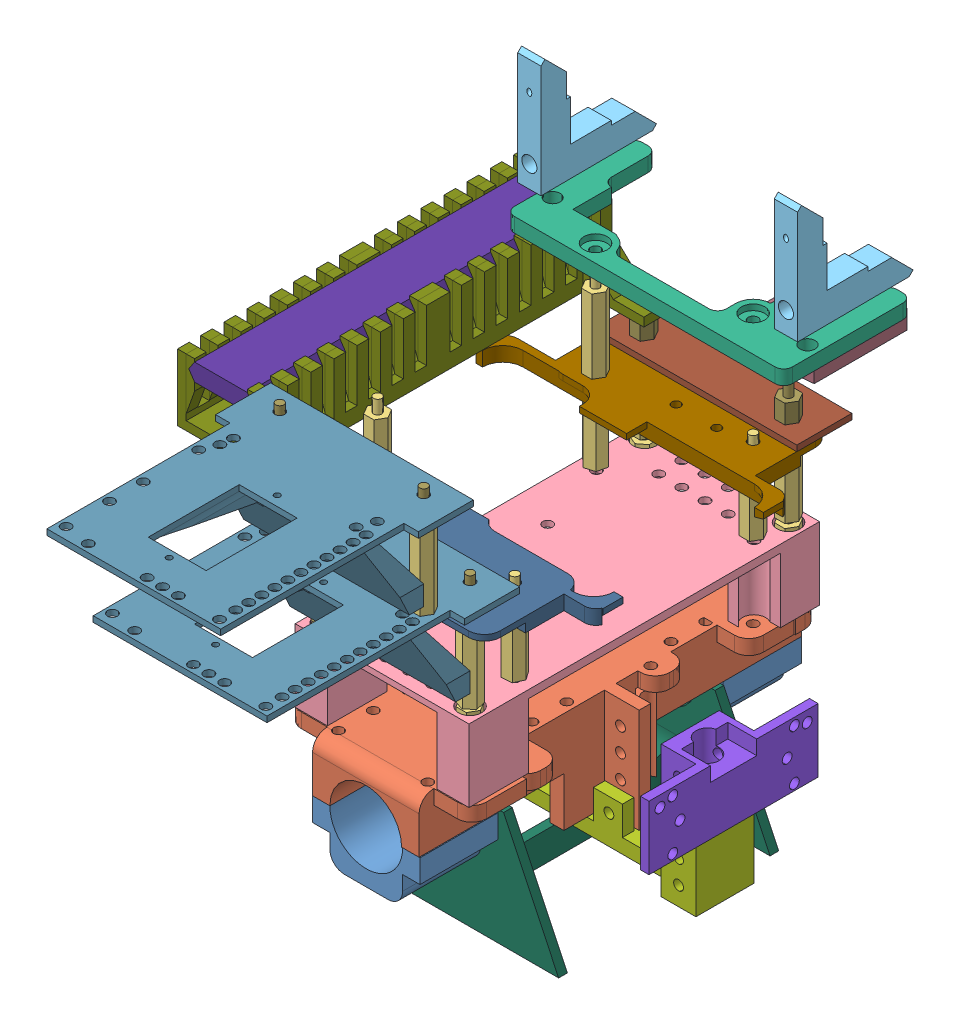
SolidWorks assembly Assemblage5, configuration Défaut. Lengths in mm.
Overall size (134 197.56 254.27).
40 component instances, 17 part files, 85 mates.
Components (placement in the parent):
- Pièce2b-1: Pièce2b [Défaut] at (-3.667 32.9905 263.0949) x (1 0 0) z (0 0 -1) size (37.12 18 27)
- Pièce2b-2: Pièce2b [Défaut] at (-3.9871 32.9905 131.0949) x (-1 0 0) z (0 0 1) size (37.12 18 27)
- Pièce1c-1: Pièce1c [Défaut] at (-3.827 32.9905 131.0949) size (72.97 36 132.85)
- exagone1-6: exagone1 [Défaut] at (-27.807 77.9905 235.0174) x (-0.458196 0 -0.888851) z (0 1 0) size (7.1 6.15 30.2)
- exagone1-7: exagone1 [Défaut] at (-27.807 77.9905 159.7774) x (0.957839 0 -0.287305) z (0 1 0) size (7.1 6.15 30.2)
- exagone1-8: exagone1 [Défaut] at (20.393 77.9905 153.5574) x (1 0 0) z (0 1 0) size (7.1 6.15 30.2)
- exagone1-9: exagone1 [Défaut] at (20.6941 77.236 236.1549) x (-0.419433 0 0.907787) z (0 1 0) size (7.1 6.15 30.2)
- exagone1-10: exagone1 [Défaut] at (-27.807 105.4905 235.0174) x (1 0 0) z (0 1 0) size (7.1 6.15 30.2)
- exagone1-11: exagone1 [Défaut] at (-27.807 105.4905 159.7774) x (1 0 0.000039) z (0 1 0) size (7.1 6.15 30.2)
- support_batterie_portable1-1: support_batterie_portable1 [Défaut] at (10.2075 50.9905 203.6226) x (1 0 0) z (0 1 0) size (60 121.05 25)
- exagone1-12: exagone1 [Défaut] at (21.173 50.9905 142.0949) x (1 0 0) z (0 1 0) size (7.1 6.15 30.2)
- exagone1-13: exagone1 [Défaut] at (-28.827 50.9905 142.0949) x (0.791864 0 -0.610698) z (0 1 0) size (7.1 6.15 30.2)
- exagone1-14: exagone1 [Défaut] at (-28.827 50.9905 252.0949) x (1 0 0) z (0 1 0) size (7.1 6.15 30.2)
- exagone1-15: exagone1 [Défaut] at (21.173 50.9905 252.0949) x (1 0 0) z (0 1 0) size (7.1 6.15 30.2)
- support02-1: support02 [Défaut] at (-44.8171 185.6386 155.3707) x (-0.004818 -0.707107 -0.70709) z (-0.999977 0 0.006814) size (54.89 29.35 8)
- support02-2: support02 [Défaut] at (43.1809 185.6386 154.7711) x (-0.004818 -0.707107 -0.70709) z (-0.999977 0 0.006814) size (54.89 29.35 8)
- ecran supplementaire2-1: ecran supplementaire2 [Défaut] at (39.1725 138.7883 153.5574) x (-1 0 0) z (0 1 0) size (96 44.22 5)
- stabilizer2-1: stabilizer2 [Défaut] at (-4.2222 13.9905 199.0949) x (1 0 0) z (0 -1 0) size (120.8 20 21)
- support_sensor_01-1: support_sensor_01 [Défaut] at (44.1778 32.671 209.0949) x (0 0 -1) z (1 0 0) size (58.42 22 15)
- support_raspberry_gouche_01-1: support_raspberry_gouche_01 [Défaut] at (79.6593 103.4905 220.4967) x (1 0 0) z (0 1 0) size (99.29 35.95 5)
- support_raspberry_droit_01-2: support_raspberry_droit_01 [Défaut] at (79.9605 102.736 220.4912) x (1 0 0) z (0 1 0) size (99.3 36.77 5)
- exagone1-16: exagone1 [Défaut] at (21.173 77.236 252.0949) x (0.224036 0 0.974581) z (0 1 0) size (7.1 6.15 30.2)
- exagone1-17: exagone1 [Défaut] at (-28.827 77.236 252.0949) x (1 0 0) z (0 1 0) size (7.1 6.15 30.2)
- exagone1-18: exagone1 [Défaut] at (-28.827 77.9905 142.0949) x (1 0 0) z (0 1 0) size (7.1 6.15 30.2)
- exagone1-19: exagone1 [Défaut] at (21.173 77.9905 142.0949) x (1 0 0) z (0 1 0) size (7.1 6.15 30.2)
- support_camera_web_01-1: support_camera_web_01 [Défaut] at (-28.827 107.4905 142.0949) x (0 0 1) z (0 -1 0) size (19 70 8)
- exagone_6_5-1: exagone_6_5 [Défaut] at (-28.827 107.4905 142.0949) x (1 0 0) z (0 1 0) size (7.1 6.15 11.2)
- exagone_6_5-2: exagone_6_5 [Défaut] at (21.173 107.4905 142.0949) x (1 0 0) z (0 1 0) size (7.1 6.15 11.2)
- support_camera_web_02-1: support_camera_web_02 [Défaut] at (20.873 107.4905 117.0949) x (0 0 -1) z (0 -1 0) size (40 26 12.8)
- exagone_6_5-3: exagone_6_5 [Défaut] at (21.173 104.736 252.0949) x (0.994038 0 0.109035) z (0 1 0) size (7.1 6.15 11.2)
- exagone_6_5-4: exagone_6_5 [Défaut] at (-28.827 104.736 252.0949) x (1 0 0) z (0 1 0) size (7.1 6.15 11.2)
- support_experiment_02-1: support_experiment_02 [Défaut] at (21.173 113.236 252.0949) x (0 0 -1) z (0 -1 0) size (82.27 70 30)
- support_all_robot01-1: support_all_robot01 [Défaut] at (-4.727 12.9905 197.0949) x (0 0 -1) z (1 0 0) size (76 40 76)
- exagone1-20: exagone1 [Défaut] at (-28.527 113.236 268.0949) x (1 0 0) z (0 1 0) size (7.1 6.15 30.2)
- exagone1-21: exagone1 [Défaut] at (21.173 113.236 268.0949) x (1 0 0) z (0 1 0) size (7.1 6.15 30.2)
- support_experiment_02-2: support_experiment_02 [Défaut] at (21.173 147.236 268.0949) x (0 0 -1) z (0 -1 0) size (82.27 70 30)
- exagone_6_5-5: exagone_6_5 [Défaut] at (21.173 138.736 268.0949) x (0.977348 0 -0.211637) z (0 1 0) size (7.1 6.15 11.2)
- exagone_6_5-6: exagone_6_5 [Défaut] at (-28.527 138.736 268.0949) x (0.971301 0 0.237855) z (0 1 0) size (7.1 6.15 11.2)
- Range_cable_A-1: Range_cable_A [Défaut] at (-74.827 114.3335 137.0949) x (0 0 1) z (0 1 0) size (120 51 23)
- Range_cable_B-1: Range_cable_B [Défaut] at (-70.943 133.3335 137.0949) size (22.2 6 120)
Mates (geometry in assembly coordinates):
- Coaxiale1: concentric anti-aligned: cylinder of Pièce2b-1 through (-19.227 32.9905 245.0949) axis (0 -1 0) radius 1.7; cylinder of Pièce1c-1 through (-19.227 32.9905 245.0949) axis (0 1 0) radius 1.7
- Parallèle1: parallel anti-aligned: cylinder of Pièce2b-1 through (11.8931 32.9905 257.0949) axis (0 -1 0) radius 1.7; cylinder of Pièce1c-1 through (11.573 32.9905 257.0949) axis (0 1 0) radius 1.7
- Coaxiale3: concentric anti-aligned: cylinder of Pièce2b-2 through (11.573 32.9905 137.0949) axis (0 -1 0) radius 1.7; cylinder of Pièce1c-1 through (11.573 32.9905 137.0949) axis (0 1 0) radius 1.7
- Parallèle2: parallel anti-aligned: cylinder of Pièce2b-2 through (-19.5472 32.9905 137.0949) axis (0 -1 0) radius 1.7; cylinder of Pièce1c-1 through (-19.227 32.9905 137.0949) axis (0 1 0) radius 1.7
- Coïncidente1: coincident anti-aligned: plane of Pièce2b-2 through (8.573 32.9905 158.0949) normal (0 1 0); plane of Pièce1c-1 through (-16.227 32.9905 263.0949) normal (0 -1 0)
- Coïncidente2: coincident anti-aligned: plane of Pièce2b-1 through (8.8931 32.9905 236.0949) normal (0 1 0); plane of Pièce1c-1 through (-16.227 32.9905 263.0949) normal (0 -1 0)
- Coaxiale27: concentric aligned: cylinder of exagone1-6 through (-27.807 108.1905 235.0174) axis (0 -1 0) radius 1.385; cylinder of exagone1-10 through (-27.807 110.1905 235.0174) axis (0 -1 0) radius 1.35
- Coaxiale28: concentric aligned: cylinder of exagone1-7 through (-27.807 108.1905 159.7774) axis (0 -1 0) radius 1.385; cylinder of exagone1-11 through (-27.807 110.1905 159.7774) axis (0 -1 0) radius 1.35
- Coïncidente35: coincident anti-aligned: plane of Pièce1c-1 through (-22.227 50.9905 263.0949) normal (0 1 0); plane of support_batterie_portable1-1 through (10.2075 50.9905 203.6226) normal (0 -1 0)
- Coïncidente37: coincident anti-aligned: plane of Pièce1c-1 through (-22.227 50.9905 263.0949) normal (0 1 0); plane of exagone1-12 through (21.173 50.9905 142.0949) normal (0 -1 0)
- Coaxiale29: concentric anti-aligned: cylinder of Pièce1c-1 through (21.173 35.9905 142.0949) axis (0 1 0) radius 1.7; cylinder of exagone1-12 through (21.173 55.6905 142.0949) axis (0 -1 0) radius 1.35
- Coaxiale32: concentric anti-aligned: cylinder of Pièce1c-1 through (21.173 35.9905 142.0949) axis (0 1 0) radius 1.7; cylinder of support_batterie_portable1-1 through (21.173 75.9905 142.0949) axis (0 -1 0) radius 4
- Coaxiale33: concentric anti-aligned: cylinder of Pièce1c-1 through (-28.827 35.9905 142.0949) axis (0 1 0) radius 1.7; circle of exagone1-13
- Coïncidente38: coincident anti-aligned: plane of Pièce1c-1 through (-22.227 50.9905 263.0949) normal (0 1 0); plane of exagone1-13 through (-28.827 50.9905 142.0949) normal (0 -1 0)
- Coaxiale34: concentric anti-aligned: cylinder of Pièce1c-1 through (-28.827 35.9905 252.0949) axis (0 1 0) radius 1.7; cylinder of exagone1-14 through (-28.827 55.6905 252.0949) axis (0 -1 0) radius 1.35
- Coïncidente39: coincident anti-aligned: plane of Pièce1c-1 through (-22.227 50.9905 263.0949) normal (0 1 0); plane of exagone1-14 through (-28.827 50.9905 252.0949) normal (0 -1 0)
- Coïncidente40: coincident anti-aligned: plane of Pièce1c-1 through (-22.227 50.9905 263.0949) normal (0 1 0); plane of exagone1-15 through (21.173 50.9905 252.0949) normal (0 -1 0)
- Coaxiale35: concentric anti-aligned: cylinder of Pièce1c-1 through (21.173 35.9905 252.0949) axis (0 1 0) radius 1.7; cylinder of exagone1-15 through (21.173 55.6905 252.0949) axis (0 -1 0) radius 1.35
- Coaxiale37: concentric aligned: cylinder of support_batterie_portable1-1 through (21.173 75.9905 252.0949) axis (0 -1 0) radius 4; cylinder of exagone1-15 through (21.173 81.1905 252.0949) axis (0 -1 0) radius 1.385
- Coaxiale40: concentric anti-aligned: cylinder of Pièce1c-1 through (20.393 42.9905 153.5574) axis (0 1 0) radius 1.7; cylinder of exagone1-8 through (20.393 82.6905 153.5574) axis (0 -1 0) radius 1.35
- Coïncidente46: coincident aligned: plane of support02-1 through (-52.7743 150.3883 161.6841) normal (0.006814 0 0.999977); plane of support02-2 through (35.2237 150.3883 161.0845) normal (0.006814 0 0.999977)
- Distance1: distance = 80 mm anti-aligned: plane of support02-2 through (35.181 185.6386 154.8256) normal (-0.999977 0 0.006814); plane of support02-1 through (-44.8171 185.6386 155.3707) normal (0.999977 0 -0.006814)
- Distance2: distance = 2 mm anti-aligned: plane of exagone1-7 through (-27.807 77.9905 159.7774) normal (0 -1 0); plane of support_batterie_portable1-1 through (10.2075 75.9905 203.6226) normal (0 1 0)
- Coïncidente52: coincident aligned: plane of support02-1 through (-52.7743 150.3883 161.6841) normal (0 -1 0); plane of support02-2 through (35.2237 150.3883 161.0845) normal (0 -1 0)
- Coaxiale43: concentric aligned: cylinder of exagone1-8 through (20.393 108.1905 153.5574) axis (0 -1 0) radius 1.385; cylinder of ecran supplementaire2-1 through (20.393 143.7883 153.5574) axis (0 -1 0) radius 1.7
- Coaxiale44: concentric anti-aligned: circle of support02-2; circle of ecran supplementaire2-1
- Distance3: distance = 6.6 mm anti-aligned: plane of support02-2 through (35.2237 150.3883 161.0845) normal (0 -1 0); plane of ecran supplementaire2-1 through (40.1725 143.7883 162.7774) normal (0 1 0)
- Coaxiale48: concentric aligned: cylinder of Pièce1c-1 through (20.1278 18.9905 187.0949) axis (0 0 1) radius 1.7; cylinder of stabilizer2-1 through (20.1278 18.9905 193.0949) axis (0 0 1) radius 1.7
- Parallèle16: parallel anti-aligned: plane of Pièce1c-1 through (-3.827 15.9905 131.0949) normal (0 -1 0); plane of stabilizer2-1 through (-4.2222 13.9905 199.0949) normal (0 1 0)
- Coïncidente57: coincident anti-aligned: plane of Pièce1c-1 through (26.573 14.9905 199.0949) normal (0 0 1); plane of stabilizer2-1 through (14.7778 23.9905 199.0949) normal (0 0 -1)
- Coaxiale49: concentric aligned: cylinder of stabilizer2-1 through (50.1778 5.9905 199.0949) axis (0 1 0) radius 4; cylinder of support_sensor_01-1 through (50.1778 28.671 199.0949) axis (0 1 0) radius 4
- Coïncidente58: coincident aligned: plane of stabilizer2-1 through (44.1778 8.9905 209.0949) normal (-1 0 0); plane of support_sensor_01-1 through (44.1778 32.671 209.0949) normal (-1 0 0)
- Coaxiale50: concentric aligned: cylinder of exagone1-8 through (20.393 108.1905 153.5574) axis (0 -1 0) radius 1.385; cylinder of support_raspberry_gouche_01-1 through (20.393 106.4905 153.5574) axis (0 -1 0) radius 1.7
- Coaxiale51: concentric aligned: cylinder of exagone1-7 through (-27.807 108.1905 159.7774) axis (0 -1 0) radius 1.385; cylinder of support_raspberry_gouche_01-1 through (-27.807 106.4905 159.7774) axis (0 -1 0) radius 1.7
- Parallèle18: parallel aligned: plane of support_batterie_portable1-1 through (-33.6765 75.9905 136.5694) normal (0 0 -1); plane of support_raspberry_gouche_01-1 through (30.969 106.4905 147.7774) normal (0 0 -1)
- Coïncidente60: coincident anti-aligned: plane of exagone1-8 through (20.393 103.4905 153.5574) normal (0 1 0); plane of support_raspberry_gouche_01-1 through (-32.5208 103.4905 160.8016) normal (0 -1 0)
- Coïncidente61: coincident anti-aligned: plane of exagone1-7 through (-27.807 103.4905 159.7774) normal (0 1 0); plane of support_raspberry_gouche_01-1 through (-32.5208 103.4905 160.8016) normal (0 -1 0)
- Coaxiale53: concentric aligned: cylinder of exagone1-9 through (20.6941 107.436 236.1549) axis (0 -1 0) radius 1.385; cylinder of support_raspberry_droit_01-2 through (20.6941 105.736 236.1549) axis (0 -1 0) radius 1.7
- Coïncidente62: coincident anti-aligned: plane of exagone1-9 through (20.6941 102.736 236.1549) normal (0 1 0); plane of support_raspberry_droit_01-2 through (-32.2196 102.736 153.2719) normal (0 -1 0)
- Parallèle19: parallel aligned: plane of support_batterie_portable1-1 through (-33.6765 75.9905 257.6204) normal (0 0 1); plane of support_raspberry_droit_01-2 through (32.594 105.736 244.4132) normal (0 0 1)
- Coaxiale54: concentric aligned: cylinder of exagone1-9 through (20.6941 81.936 236.1549) axis (0 -1 0) radius 1.35; cylinder of support_batterie_portable1-1 through (20.6941 75.9905 236.1549) axis (0 -1 0) radius 1.7
- Coaxiale55: concentric aligned: cylinder of exagone1-15 through (21.173 81.1905 252.0949) axis (0 -1 0) radius 1.385; cylinder of exagone1-16 through (21.173 81.936 252.0949) axis (0 -1 0) radius 1.35
- Coïncidente64: coincident anti-aligned: plane of support_raspberry_droit_01-2 through (-32.2196 102.736 153.2719) normal (0 -1 0); plane of exagone1-16 through (21.173 102.736 252.0949) normal (0 1 0)
- Coaxiale56: concentric aligned: cylinder of exagone1-14 through (-28.827 81.1905 252.0949) axis (0 -1 0) radius 1.385; cylinder of exagone1-17 through (-28.827 81.936 252.0949) axis (0 -1 0) radius 1.35
- Coïncidente66: coincident anti-aligned: plane of support_raspberry_droit_01-2 through (-32.2196 102.736 153.2719) normal (0 -1 0); plane of exagone1-17 through (-28.827 102.736 252.0949) normal (0 1 0)
- Coaxiale57: concentric aligned: cylinder of exagone1-13 through (-28.827 81.1905 142.0949) axis (0 -1 0) radius 1.385; cylinder of exagone1-18 through (-28.827 82.6905 142.0949) axis (0 -1 0) radius 1.35
- Coïncidente67: coincident anti-aligned: plane of support_raspberry_gouche_01-1 through (-32.5208 103.4905 160.8016) normal (0 -1 0); plane of exagone1-18 through (-28.827 103.4905 142.0949) normal (0 1 0)
- Coaxiale58: concentric aligned: cylinder of exagone1-12 through (21.173 81.1905 142.0949) axis (0 -1 0) radius 1.385; cylinder of exagone1-19 through (21.173 82.6905 142.0949) axis (0 -1 0) radius 1.35
- Coïncidente68: coincident anti-aligned: plane of support_raspberry_gouche_01-1 through (-32.5208 103.4905 160.8016) normal (0 -1 0); plane of exagone1-19 through (21.173 103.4905 142.0949) normal (0 1 0)
- Coïncidente69: coincident anti-aligned: plane of support_camera_web_01-1 through (-28.827 107.4905 142.0949) normal (0 1 0); plane of exagone_6_5-2 through (21.173 107.4905 142.0949) normal (0 -1 0)
- Coaxiale60: concentric aligned: cylinder of exagone1-19 through (21.173 108.1905 142.0949) axis (0 -1 0) radius 1.385; cylinder of exagone_6_5-2 through (21.173 112.1905 142.0949) axis (0 -1 0) radius 1.35
- Coïncidente70: coincident anti-aligned: plane of support_camera_web_01-1 through (-28.827 107.4905 142.0949) normal (0 1 0); plane of exagone_6_5-1 through (-28.827 107.4905 142.0949) normal (0 -1 0)
- Coaxiale61: concentric aligned: cylinder of exagone1-18 through (-28.827 108.1905 142.0949) axis (0 -1 0) radius 1.385; cylinder of exagone_6_5-1 through (-28.827 112.1905 142.0949) axis (0 -1 0) radius 1.35
- Coaxiale62: concentric anti-aligned: cylinder of support_camera_web_01-1 through (-28.827 105.4905 142.0949) axis (0 1 0) radius 1.7; cylinder of exagone_6_5-1 through (-28.827 118.6905 142.0949) axis (0 -1 0) radius 1.385
- Coïncidente71: coincident anti-aligned: plane of support_raspberry_gouche_01-1 through (79.6593 105.4905 220.4967) normal (0 1 0); plane of support_camera_web_01-1 through (-28.827 105.4905 142.0949) normal (0 -1 0)
- Parallèle20: parallel aligned: plane of support_raspberry_gouche_01-1 through (-32.5208 106.4905 137.0949) normal (0 0 -1); plane of support_camera_web_01-1 through (-38.977 105.4905 130.0949) normal (0 0 -1)
- Coaxiale63: concentric anti-aligned: cylinder of support_camera_web_01-1 through (-3.977 102.4905 134.0949) axis (0 0 -1) radius 1.4; cylinder of support_camera_web_02-1 through (-3.977 102.4905 125.0949) axis (0 0 1) radius 1.4
- Distance4: distance = 1 mm anti-aligned: plane of support_camera_web_01-1 through (-38.977 105.4905 130.0949) normal (0 0 -1); plane of support_camera_web_02-1 through (9.023 105.4905 129.0949) normal (0 0 1)
- Coïncidente74: coincident aligned: plane of support_camera_web_01-1 through (-28.827 107.4905 142.0949) normal (0 1 0); plane of support_camera_web_02-1 through (20.873 107.4905 117.0949) normal (0 1 0)
- Coaxiale64: concentric aligned: cylinder of exagone1-11 through (-27.807 135.6905 159.7774) axis (0 -1 0) radius 1.385; cylinder of ecran supplementaire2-1 through (-27.807 143.7883 159.7774) axis (0 -1 0) radius 1.7
- Coaxiale67: concentric aligned: cylinder of exagone1-16 through (21.173 107.436 252.0949) axis (0 -1 0) radius 1.385; cylinder of exagone_6_5-3 through (21.173 109.436 252.0949) axis (0 -1 0) radius 1.35
- Coïncidente76: coincident anti-aligned: plane of support_raspberry_droit_01-2 through (79.9605 104.736 220.4912) normal (0 1 0); plane of exagone_6_5-3 through (21.173 104.736 252.0949) normal (0 -1 0)
- Coaxiale68: concentric aligned: cylinder of exagone1-17 through (-28.827 107.436 252.0949) axis (0 -1 0) radius 1.385; cylinder of exagone_6_5-4 through (-28.827 109.436 252.0949) axis (0 -1 0) radius 1.35
- Coïncidente78: coincident anti-aligned: plane of support_raspberry_droit_01-2 through (79.9605 104.736 220.4912) normal (0 1 0); plane of exagone_6_5-4 through (-28.827 104.736 252.0949) normal (0 -1 0)
- Parallèle21: parallel anti-aligned: plane of support_raspberry_droit_01-2 through (-33.4301 105.736 258.5519) normal (0 0 1); plane of support_experiment_02-1 through (31.323 111.236 245.0949) normal (0 0 -1)
- Distance5: distance = 1 mm anti-aligned: plane of support_all_robot01-1 through (-3.227 32.9905 235.0949) normal (0 0 1); plane of Pièce2b-1 through (-3.667 32.9905 236.0949) normal (0 0 -1)
- Coïncidente81: coincident anti-aligned: plane of Pièce1c-1 through (-16.227 32.9905 263.0949) normal (0 -1 0); plane of support_all_robot01-1 through (-16.227 32.9905 235.0949) normal (0 1 0)
- Distance6: distance = 0 mm: line of support_all_robot01-1 through (-22.227 32.9905 235.0949) axis (0 0 -1); line of Pièce1c-1 through (-22.227 32.9905 263.0949) axis (0 0 -1)
- Coaxiale69: concentric anti-aligned: cylinder of exagone_6_5-3 through (21.173 115.936 252.0949) axis (0 -1 0) radius 1.385; cylinder of support_experiment_02-1 through (21.173 111.236 252.0949) axis (0 1 0) radius 1.7
- Coïncidente82: coincident anti-aligned: plane of exagone_6_5-3 through (21.173 111.236 252.0949) normal (0 1 0); plane of support_experiment_02-1 through (21.173 111.236 252.0949) normal (0 -1 0)
- Coaxiale70: concentric anti-aligned: cylinder of support_experiment_02-1 through (-28.527 111.236 268.0949) axis (0 1 0) radius 1.7; cylinder of exagone1-20 through (-28.527 117.936 268.0949) axis (0 -1 0) radius 1.35
- Coïncidente83: coincident anti-aligned: plane of support_experiment_02-1 through (21.173 113.236 252.0949) normal (0 1 0); plane of exagone1-20 through (-28.527 113.236 268.0949) normal (0 -1 0)
- Coaxiale71: concentric anti-aligned: cylinder of support_experiment_02-1 through (21.173 111.236 268.0949) axis (0 1 0) radius 1.7; cylinder of exagone1-21 through (21.173 117.936 268.0949) axis (0 -1 0) radius 1.35
- Coïncidente84: coincident anti-aligned: plane of support_experiment_02-1 through (21.173 113.236 252.0949) normal (0 1 0); plane of exagone1-21 through (21.173 113.236 268.0949) normal (0 -1 0)
- Coaxiale72: concentric anti-aligned: cylinder of exagone1-21 through (21.173 143.436 268.0949) axis (0 -1 0) radius 1.385; cylinder of support_experiment_02-2 through (21.173 145.236 268.0949) axis (0 1 0) radius 1.7
- Parallèle22: parallel aligned: plane of support_experiment_02-1 through (31.323 111.236 245.0949) normal (0 0 -1); plane of support_experiment_02-2 through (31.323 145.236 261.0949) normal (0 0 -1)
- Coaxiale73: concentric aligned: cylinder of exagone1-21 through (21.173 143.436 268.0949) axis (0 -1 0) radius 1.385; cylinder of exagone_6_5-5 through (21.173 143.436 268.0949) axis (0 -1 0) radius 1.35
- Coïncidente86: coincident anti-aligned: plane of exagone1-21 through (21.173 138.736 268.0949) normal (0 1 0); plane of exagone_6_5-5 through (21.173 138.736 268.0949) normal (0 -1 0)
- Coaxiale74: concentric aligned: cylinder of exagone1-20 through (-28.527 143.436 268.0949) axis (0 -1 0) radius 1.385; cylinder of exagone_6_5-6 through (-28.527 143.436 268.0949) axis (0 -1 0) radius 1.35
- Coïncidente87: coincident anti-aligned: plane of exagone1-20 through (-28.527 138.736 268.0949) normal (0 1 0); plane of exagone_6_5-6 through (-28.527 138.736 268.0949) normal (0 -1 0)
- Coïncidente88: coincident anti-aligned: plane of support_experiment_02-2 through (21.173 145.236 268.0949) normal (0 -1 0); plane of exagone_6_5-5 through (21.173 145.236 268.0949) normal (0 1 0)
- Coaxiale75: concentric aligned: cylinder of exagone_6_5-4 through (-28.827 115.936 252.0949) axis (0 -1 0) radius 1.385; cylinder of Range_cable_A-1 through (-28.827 117.3335 252.0949) axis (0 -1 0) radius 1.7
- Coaxiale76: concentric aligned: cylinder of exagone_6_5-1 through (-28.827 118.6905 142.0949) axis (0 -1 0) radius 1.385; cylinder of Range_cable_A-1 through (-28.827 117.3335 142.0949) axis (0 -1 0) radius 1.7
- Coïncidente89: coincident anti-aligned: line of Range_cable_A-1 through (-70.943 133.3335 253.0949) axis (0 0 1); line of Range_cable_B-1 through (-70.943 133.3335 257.0949) axis (0 0 -1)
- Coïncidente90: coincident aligned: plane of Range_cable_A-1 through (-74.827 114.3335 257.0949) normal (0 0 1); plane of Range_cable_B-1 through (-70.943 133.3335 257.0949) normal (0 0 1)
